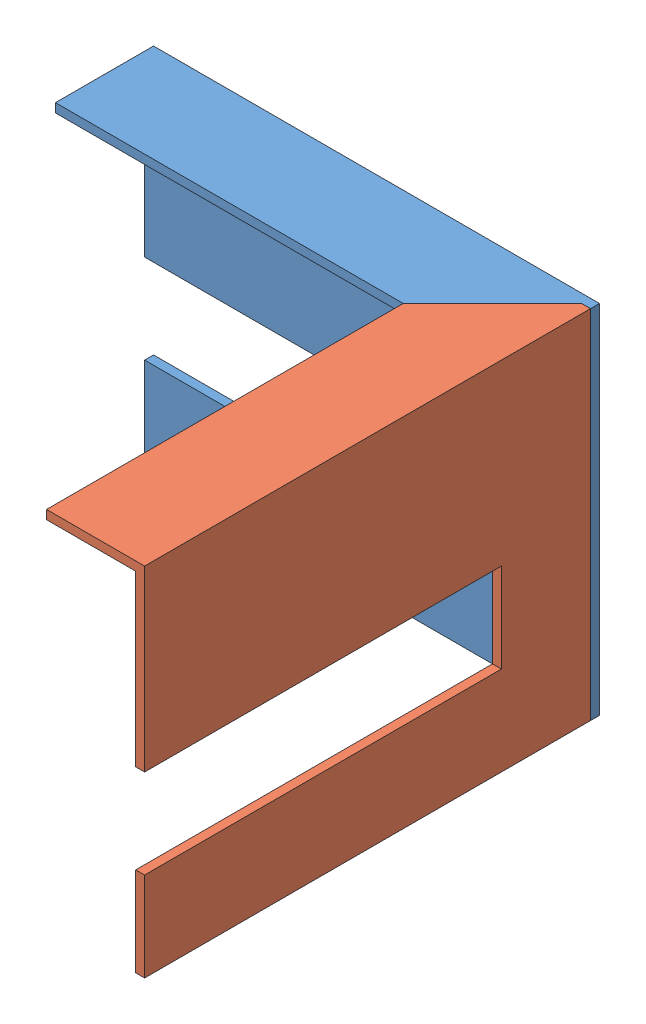
SolidWorks assembly 装配体1, configuration 默认. Lengths in mm.
Overall size (50 40 51).
2 component instances, 2 part files, 3 mates.
Components (placement in the parent):
- 零件1-1: 零件1 [默认] at (-1.8498 8.9175 50.0001) size (50 40 11)
- 零件2-2: 零件2 [默认] at (20.647 6.3614 80.8871) x (0 0 -1) z (1 0 0) size (50 40 11)
Mates (geometry in assembly coordinates):
- 重合6: coincident anti-aligned: plane of 零件1-1 through (-1.8498 8.9175 51.0001) normal (0 0 1); plane of 零件2-2 through (21.647 18.3162 51.0001) normal (0 0 -1)
- 重合7: coincident aligned: line of 零件1-1 through (21.647 -21.6838 51.0001) axis (0 1 0); line of 零件2-2 through (21.647 -21.6838 51.0001) axis (0 1 0)
- 重合8: coincident: point of 零件1-1; point of 零件2-2
